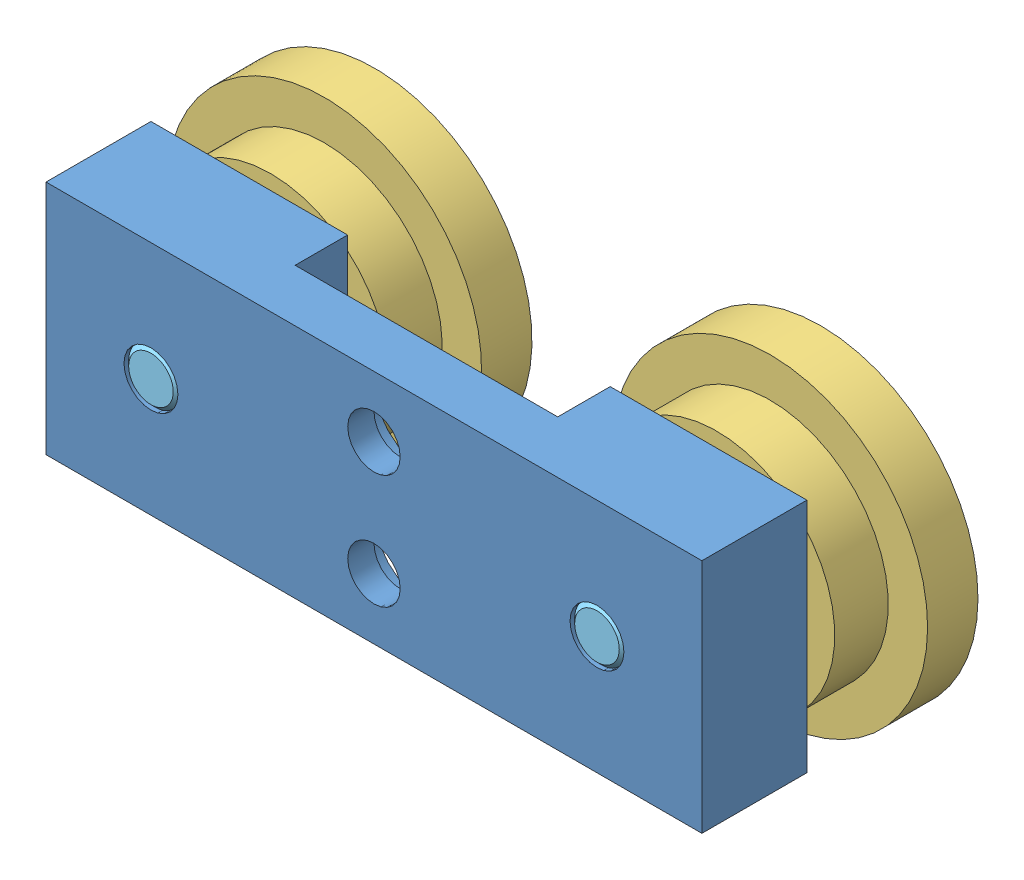
SolidWorks assembly 2018-505-A(custom), configuration Default. Lengths in mm.
Overall size (92.8 39.35 32.25).
9 component instances, 5 part files, 17 mates.
Components (placement in the parent):
- 2018-505-D001-1: 2018-505-D001 [Default] at origin size (79.38 28.57 12.7)
- 2018-505-D003-1: 2018-505-D003 [Default] at (-26.9875 14.2875 -14.2748) x (1 0 0) z (0 -1 0) size (22.23 1.57 22.23)
- 2018-505-D003-2: 2018-505-D003 [Default] at (26.9875 14.2875 -14.2748) x (0 1 0) z (1 0 0) size (22.23 1.57 22.23)
- 2018-505-D006-1: 2018-505-D006 [Default] at (-26.9875 14.2875 -14.4875) x (-0.999439 0.033487 0) z (0 0 1) size (38.1 38.1 15.62)
- 2018-505-D006-2: 2018-505-D006 [Default] at (26.9875 14.2875 -14.4875) x (-0.999987 0.005154 0) z (0 0 1) size (38.1 38.1 15.62)
- 2018-505-D004-1: 2018-505-D004 [60355K45] at (-26.9875 14.2875 -21.6154) x (-1 0 0) z (0 0 -1) size (22.23 22.23 7.14)
- 2018-505-D004-3: 2018-505-D004 [60355K45] at (26.9875 14.2875 -21.6154) x (-1 0 0) z (0 0 -1) size (22.23 22.23 7.14)
- 2018-505-D007_375x500ShoulderBolt91259A619-1: 2018-505-D007_375x500ShoulderBolt91259A619 [91259A623] at (-26.9875 14.2875 -25.4) x (0 -1 0) z (1 0 0) size (14.29 32.25 14.29)
- 2018-505-D007_375x500ShoulderBolt91259A619-2: 2018-505-D007_375x500ShoulderBolt91259A619 [91259A623] at (26.9875 14.2875 -25.4) x (0 -1 0) z (1 0 0) size (14.29 32.25 14.29)
Mates (geometry in assembly coordinates):
- Coincident1: coordinate: point of 2018-505-D001-1; point of assembly
- Concentric1: concentric aligned: cylinder of 2018-505-D006-1 through (-26.9875 14.2875 -18.0435) axis (0 0 -1) radius 11.1125; cylinder of 2018-505-D004-1 through (-26.9875 14.2875 -25.1873) axis (0 0 -1) radius 11.1125
- Concentric2: concentric aligned: cylinder of 2018-505-D006-2 through (26.9875 14.2875 -60.5239) axis (0 0 -1) radius 11.1125; cylinder of 2018-505-D004-3 through (26.9875 14.2875 -67.6677) axis (0 0 -1) radius 11.1125
- Coincident2: coincident anti-aligned: plane of 2018-505-D006-1 through (-26.9875 14.2875 -18.0435) normal (0 0 -1); plane of 2018-505-D004-1 through (-26.9875 25.0428 -18.0435) normal (0 0 1)
- Coincident3: coincident anti-aligned: plane of 2018-505-D006-2 through (26.9875 14.2875 -60.5239) normal (0 0 -1); plane of 2018-505-D004-3 through (26.9875 25.0428 -60.5239) normal (0 0 1)
- Concentric3: concentric anti-aligned: cylinder of 2018-505-D001-1 through (-26.9875 14.2875 -12.7) axis (0 0 -1) radius 3.2639; cylinder of 2018-505-D007_375x500ShoulderBolt91259A619-1 through (-26.9875 14.2875 -25.4) axis (0 0 1) radius 4.7625
- Concentric4: concentric anti-aligned: cylinder of 2018-505-D001-1 through (26.9875 14.2875 -12.7) axis (0 0 -1) radius 3.2639; cylinder of 2018-505-D007_375x500ShoulderBolt91259A619-2 through (26.9875 14.2875 -25.4) axis (0 0 1) radius 4.7625
- Concentric5: concentric anti-aligned: cylinder of 2018-505-D003-1 through (-26.9875 14.2875 -12.7) axis (0 0 -1) radius 4.9784; cylinder of 2018-505-D007_375x500ShoulderBolt91259A619-1 through (-26.9875 14.2875 -25.4) axis (0 0 1) radius 4.7625
- Concentric6: concentric anti-aligned: cylinder of 2018-505-D003-2 through (26.9875 14.2875 -12.7) axis (0 0 -1) radius 4.9784; cylinder of 2018-505-D007_375x500ShoulderBolt91259A619-2 through (26.9875 14.2875 -25.4) axis (0 0 1) radius 4.7625
- Coincident4: coincident anti-aligned: plane of 2018-505-D001-1 through (-15.8877 28.575 -12.7) normal (0 0 -1); plane of 2018-505-D003-1 through (-26.9875 14.2875 -12.7) normal (0 0 1)
- Coincident5: coincident anti-aligned: plane of 2018-505-D001-1 through (39.6875 28.575 -12.7) normal (0 0 -1); plane of 2018-505-D003-2 through (26.9875 14.2875 -12.7) normal (0 0 1)
- Coincident6: coincident anti-aligned: plane of 2018-505-D001-1 through (39.6875 28.575 -12.7) normal (0 0 -1); plane of 2018-505-D007_375x500ShoulderBolt91259A619-2 through (26.9875 14.2875 -12.7) normal (0 0 1)
- Coincident7: coincident anti-aligned: plane of 2018-505-D001-1 through (-15.8877 28.575 -12.7) normal (0 0 -1); plane of 2018-505-D007_375x500ShoulderBolt91259A619-1 through (-26.9875 14.2875 -12.7) normal (0 0 1)
- Concentric7: concentric anti-aligned: cylinder of 2018-505-D004-1 through (-26.9875 14.2875 -25.1873) axis (0 0 -1) radius 4.7625; cylinder of 2018-505-D007_375x500ShoulderBolt91259A619-1 through (-26.9875 14.2875 -25.4) axis (0 0 1) radius 4.7625
- Concentric8: concentric anti-aligned: cylinder of 2018-505-D004-3 through (26.9875 14.2875 -25.1873) axis (0 0 -1) radius 4.7625; cylinder of 2018-505-D007_375x500ShoulderBolt91259A619-2 through (26.9875 14.2875 -25.4) axis (0 0 1) radius 4.7625
- Width1: width anti-aligned: plane of 2018-505-D006-1 through (-26.9875 14.2875 -14.4875) normal (0 0 1); plane of 2018-505-D004-1 through (-26.9875 21.5621 -25.1873) normal (0 0 -1); plane of 2018-505-D003-1 through (-26.9875 14.2875 -14.2748) normal (0 0 -1); plane of 2018-505-D007_375x500ShoulderBolt91259A619-1 through (-26.9875 14.2875 -25.4) normal (0 0 1)
- Width2: width anti-aligned: plane of 2018-505-D006-2 through (26.9875 14.2875 -14.4875) normal (0 0 1); plane of 2018-505-D004-3 through (26.9875 21.5621 -25.1873) normal (0 0 -1); plane of 2018-505-D003-2 through (26.9875 14.2875 -14.2748) normal (0 0 -1); plane of 2018-505-D007_375x500ShoulderBolt91259A619-2 through (26.9875 14.2875 -25.4) normal (0 0 1)
